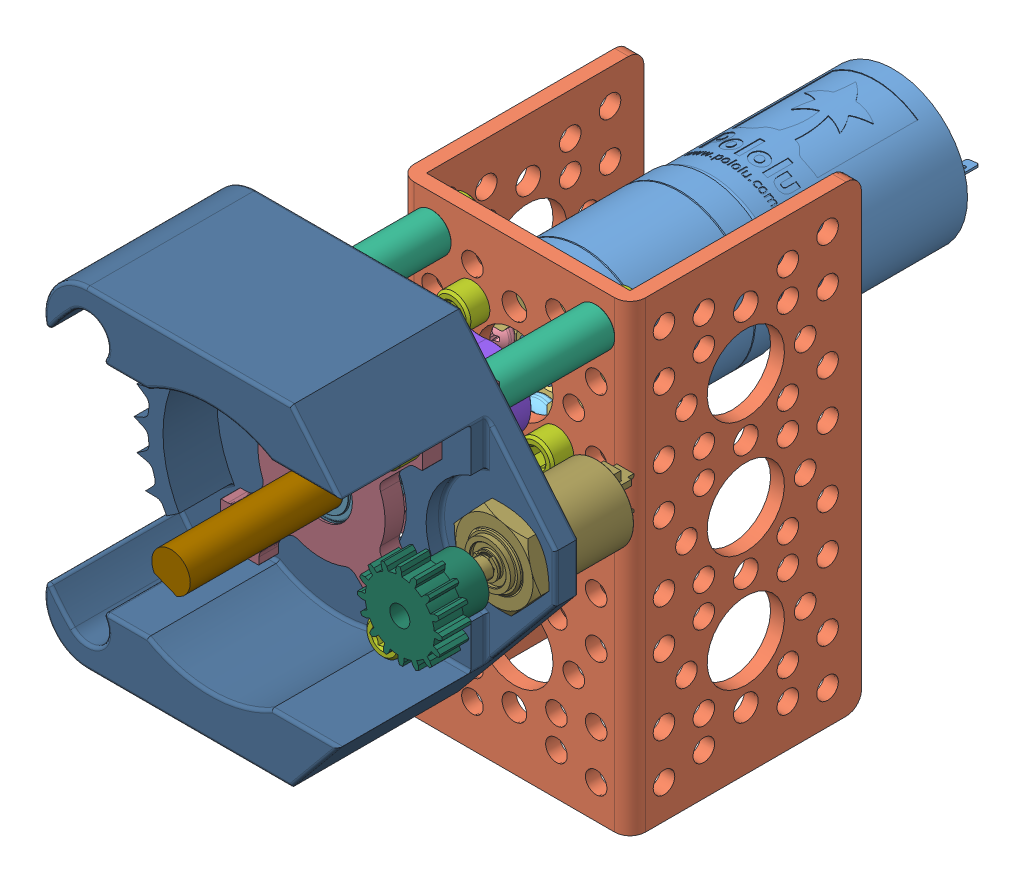
SolidWorks assembly Corner Steering Assembly, configuration Clockwise. Lengths in mm.
Overall size (61.41 84.4 123.14).
39 component instances, 15 part files, 66 mates.
Components (placement in the parent):
- 25mm Motor-1: 25mm Motor [Default] at (-12.6524 50.0026 57.4227) size (25 25 72.5)
- 3 Aluminum Channel-1: 3 Aluminum Channel [Default] at (-0.8274 -7.1474 82.4017) x (1 0 0) z (0 1 0) size (38.1 38.1 76.2)
- Motor mount f-1: Motor mount f [Default] at (-52.2349 29.3985 53.5592) x (-1 0 0) z (0 1 0) size (25.4 7.22 25.4)
  - 555104-1: 555104 [Default] at (-70.4575 22.2385 20.6041) size (25.4 4.54 25.4)
  - 555104 screw (M2.6)_92005A056-1: 555104 screw (M2.6)_92005A056 [Default] at (-77.9575 19.5085 20.6041) x (1 0 0) z (0 1 0) size (5 5 6.06)
  - 555104 screw (M2.6)_92005A056-2: 555104 screw (M2.6)_92005A056 [Default] at (-62.9575 19.5085 20.6041) x (1 0 0) z (0 1 0) size (5 5 6.06)
  - 555104 screw (M3)_92005A112-1: 555104 screw (M3)_92005A112 [Default] at (-70.4575 19.5085 12.1041) x (1 0 0) z (0 1 0) size (6 6 6.48)
  - 555104 screw (M3)_92005A112-2: 555104 screw (M3)_92005A112 [Default] at (-70.4575 19.5085 29.1041) x (1 0 0) z (0 1 0) size (6 6 6.48)
- 6_32 standoff-1: 6_32 standoff [Default] at (4.7522 63.473 82.4017) x (1 0 0) z (0 -1 0) size (6.34 19.26 6.34)
- 6_32 standoff-2: 6_32 standoff [Default] at (31.693 63.473 82.4017) x (1 0 0) z (0 -1 0) size (6.34 19.26 6.34)
- 6_32 standoff-3: 6_32 standoff [Default] at (31.693 36.5322 82.4017) x (1 0 0) z (0 -1 0) size (6.34 19.26 6.34)
- 6_32 standoff-4: 6_32 standoff [Default] at (4.7522 36.5322 82.4017) x (1 0 0) z (0 -1 0) size (6.34 19.26 6.34)
- 6-32_SHCS-1: 6-32_SHCS [6-32 SHCS X .250] at (31.693 63.473 86.4657) x (-0.923728 -0.383049 0) z (0 0 -1) size (5.74 5.74 9.86)
- 6-32_SHCS-2: 6-32_SHCS [6-32 SHCS X .250] at (4.7522 63.473 86.4657) x (-0.923728 -0.383049 0) z (0 0 -1) size (5.74 5.74 9.86)
- 6-32_SHCS-3: 6-32_SHCS [6-32 SHCS X .250] at (4.7522 36.5322 86.4657) x (-0.923728 -0.383049 0) z (0 0 -1) size (5.74 5.74 9.86)
- 6-32_SHCS-4: 6-32_SHCS [6-32 SHCS X .250] at (31.693 36.5322 86.4657) x (-0.923728 -0.383049 0) z (0 0 -1) size (5.74 5.74 9.86)
- 6-32_SHCS-5: 6-32_SHCS [6-32 SHCS X .250] at (11.3078 43.0878 76.0517) x (0.520489 -0.853869 0) z (0 0 1) size (5.74 5.74 9.86)
- 6-32_SHCS-6: 6-32_SHCS [6-32 SHCS X .250] at (25.1374 43.0878 76.0517) x (0.854812 0.518937 0) z (0 0 1) size (5.74 5.74 9.86)
- 6-32_SHCS-7: 6-32_SHCS [6-32 SHCS X .250] at (25.1374 56.9174 76.0517) size (5.74 5.74 9.86)
- 6-32_SHCS-8: 6-32_SHCS [6-32 SHCS X .250] at (11.3078 56.9174 76.0517) size (5.74 5.74 9.86)
- 4mm - 0.25in Clamping Shaft Coupler-1: 4mm - 0.25in Clamping Shaft Coupler [Default] at (18.2226 50.0026 93.5269) x (0.352101 0.935962 0) z (-0.935962 0.352101 0) size (12.7 15.24 16.29)
- .25 D Shaft-1: .25 D Shaft [Default] at (18.2226 50.0026 94.4873) x (-0.370952 -0.928652 0) z (-0.928652 0.370952 0) size (5.65 44.45 6.35)
- Encoder mount-1: Encoder mount [Default] at (18.2226 50.0026 110.9767) x (1 0 0) z (0 1 0) size (60.02 27.97 54.51)
- 6-32_L0_25 Spacer-1: 6-32_L0_25 Spacer [Default] at (4.7522 36.5322 104.6267) x (0 0 1) z (-0.967859 0.251494 0) size (6.35 6.35 6.35)
- 6-32_L0_25 Spacer-2: 6-32_L0_25 Spacer [Default] at (31.693 36.5322 104.6267) x (0 0 1) z (-0.631957 0.775004 0) size (6.35 6.35 6.35)
- 6-32_L0_25 Spacer-3: 6-32_L0_25 Spacer [Default] at (4.7522 63.473 104.6267) x (0 0 1) z (0 1 0) size (6.35 6.35 6.35)
- 6-32_L0_25 Spacer-4: 6-32_L0_25 Spacer [Default] at (31.693 63.473 104.6267) x (0 0 1) z (0 1 0) size (6.35 6.35 6.35)
- Absolute Encoder-1: Absolute Encoder [BEARING VERSION] at (43.3686 50.0026 111.1545) x (0 0 1) z (0 -1 0) size (32.36 14.32 14.3)
- 0.25 Pillow Bearing Block-1: 0.25 Pillow Bearing Block [Default] at (-10.4858 48.289 82.9742) x (0 1 0) z (1 0 0) size (33.27 5.08 33.27)
  - 0.25 Beaing Block-1: 0.25 Beaing Block [Default] at (1.7135 18.4775 28.7084) size (33.27 5.08 33.27)
  - 0.25 Bearing-1: 0.25 Bearing [Default] at (1.7135 21.1636 28.7084) x (0.837169 0 0.546944) z (0.546944 0 -0.837169) size (12.7 4.76 12.7)
- 0.25 Pillow Bearing Block-2: 0.25 Pillow Bearing Block [Default] at (19.9362 78.711 132.6292) x (-1 0 0) z (0 -1 0) size (33.27 5.08 33.27)
  - 0.25 Beaing Block-1: 0.25 Beaing Block [Default] at (1.7135 18.4775 28.7084) size (33.27 5.08 33.27)
  - 0.25 Bearing-1: 0.25 Bearing [Default] at (1.7135 21.1636 28.7084) x (0.837169 0 0.546944) z (0.546944 0 -0.837169) size (12.7 4.76 12.7)
- 0.125in Bore 32 Pitch Shaft Mount Pinion Gear-1: 0.125in Bore 32 Pitch Shaft Mount Pinion Gear [Default] at (43.3686 50.0026 126.4072) x (-0.355189 -0.934794 0) z (0.934794 -0.355189 0) size (13.97 10.48 13.97)
- 6-32_SHCS-9: 6-32_SHCS [6-32 SHCS X .750] at (31.693 63.473 95.1017) size (5.74 5.74 22.56)
- 6-32_SHCS-10: 6-32_SHCS [6-32 SHCS X .750] at (4.7522 36.5322 95.1017) size (5.74 5.74 22.56)
- 6-32_SHCS-11: 6-32_SHCS [6-32 SHCS X .750] at (4.7522 63.473 95.1017) size (5.74 5.74 22.56)
- 6-32_SHCS-12: 6-32_SHCS [6-32 SHCS X .750] at (31.693 36.5322 95.1017) size (5.74 5.74 22.56)
Mates (geometry in assembly coordinates):
- Concentric1: concentric aligned: cylinder of 25mm Motor-1 through (18.2226 50.0026 50.7977) axis (0 0 1) radius 12.5; cylinder of 3 Aluminum Channel-1 through (18.2226 50.0026 82.4017) axis (0 0 1) radius 6.3627
- Concentric2: concentric aligned: cylinder of 3 Aluminum Channel-1 through (18.2226 50.0026 82.4017) axis (0 0 1) radius 6.3627; cylinder of Motor mount f-1/555104-1 through (18.2226 50.0026 77.0677) axis (0 0 1) radius 5
- Concentric6: concentric aligned: cylinder of 25mm Motor-1 through (18.2226 58.5026 72.9477) axis (0 0 1) radius 1.25; cylinder of Motor mount f-1/555104-1 through (18.2226 58.5026 80.1157) axis (0 0 1) radius 1.5
- Coincident2: coincident anti-aligned: plane of 25mm Motor-1 through (18.2226 50.0026 75.7977) normal (0 0 1); plane of Motor mount f-1/555104-1 through (18.2226 50.0026 75.7977) normal (0 0 -1)
- Concentric7: concentric aligned: cylinder of 3 Aluminum Channel-1 through (11.3078 56.9174 82.4017) axis (0 0 1) radius 1.778; cylinder of Motor mount f-1/555104-1 through (11.3078 56.9174 80.1157) axis (0 0 1) radius 1.3526
- Coincident4: coincident anti-aligned: plane of 3 Aluminum Channel-1 through (1.4586 69.0526 80.1157) normal (0 0 -1); plane of Motor mount f-1/555104-1 through (18.2226 50.0026 80.1157) normal (0 0 1)
- Concentric8: concentric anti-aligned: cylinder of 3 Aluminum Channel-1 through (4.7522 63.473 82.4017) axis (0 0 1) radius 1.778; cylinder of 6_32 standoff-1 through (4.7522 63.473 101.4517) axis (0 0 -1) radius 3.1712
- Concentric9: concentric aligned: cylinder of 3 Aluminum Channel-1 through (4.7522 63.473 82.4017) axis (0 0 1) radius 1.778; cylinder of 6-32_SHCS-2 through (4.7522 63.473 67.4157) axis (0 0 1) radius 2.8702
- Concentric10: concentric anti-aligned: cylinder of 3 Aluminum Channel-1 through (31.693 63.473 82.4017) axis (0 0 1) radius 1.778; cylinder of 6_32 standoff-2 through (31.693 63.473 101.4517) axis (0 0 -1) radius 3.1712
- Concentric11: concentric aligned: cylinder of 3 Aluminum Channel-1 through (31.693 63.473 82.4017) axis (0 0 1) radius 1.778; cylinder of 6-32_SHCS-1 through (31.693 63.473 67.4157) axis (0 0 1) radius 2.8702
- Concentric12: concentric anti-aligned: cylinder of 3 Aluminum Channel-1 through (31.693 36.5322 82.4017) axis (0 0 1) radius 1.778; cylinder of 6_32 standoff-3 through (31.693 36.5322 101.4517) axis (0 0 -1) radius 3.1712
- Concentric13: concentric aligned: cylinder of 3 Aluminum Channel-1 through (31.693 36.5322 82.4017) axis (0 0 1) radius 1.778; cylinder of 6-32_SHCS-4 through (31.693 36.5322 67.4157) axis (0 0 1) radius 2.8702
- Concentric14: concentric anti-aligned: cylinder of 3 Aluminum Channel-1 through (4.7522 36.5322 82.4017) axis (0 0 1) radius 1.778; cylinder of 6_32 standoff-4 through (4.7522 36.5322 101.4517) axis (0 0 -1) radius 3.1712
- Concentric15: concentric aligned: cylinder of 3 Aluminum Channel-1 through (4.7522 36.5322 82.4017) axis (0 0 1) radius 1.778; cylinder of 6-32_SHCS-3 through (4.7522 36.5322 67.4157) axis (0 0 1) radius 2.8702
- Concentric16: concentric anti-aligned: cylinder of 3 Aluminum Channel-1 through (25.1374 56.9174 82.4017) axis (0 0 1) radius 1.778; cylinder of 6-32_SHCS-7 through (25.1374 56.9174 95.1017) axis (0 0 -1) radius 2.8702
- Concentric17: concentric anti-aligned: cylinder of 3 Aluminum Channel-1 through (25.1374 43.0878 82.4017) axis (0 0 1) radius 1.778; cylinder of 6-32_SHCS-6 through (25.1374 43.0878 95.1017) axis (0 0 -1) radius 2.8702
- Concentric18: concentric anti-aligned: cylinder of 3 Aluminum Channel-1 through (11.3078 43.0878 82.4017) axis (0 0 1) radius 1.778; cylinder of 6-32_SHCS-5 through (11.3078 43.0878 95.1017) axis (0 0 -1) radius 2.8702
- Concentric19: concentric anti-aligned: cylinder of 3 Aluminum Channel-1 through (11.3078 56.9174 82.4017) axis (0 0 1) radius 1.778; cylinder of 6-32_SHCS-8 through (11.3078 56.9174 95.1017) axis (0 0 -1) radius 2.8702
- Coincident5: coincident anti-aligned: plane of 3 Aluminum Channel-1 through (37.2726 69.0526 82.4017) normal (0 0 1); plane of 6-32_SHCS-8 through (11.3078 56.9174 82.4017) normal (0 0 -1)
- Coincident6: coincident anti-aligned: plane of 3 Aluminum Channel-1 through (37.2726 69.0526 82.4017) normal (0 0 1); plane of 6-32_SHCS-7 through (25.1374 56.9174 82.4017) normal (0 0 -1)
- Coincident7: coincident anti-aligned: plane of 3 Aluminum Channel-1 through (37.2726 69.0526 82.4017) normal (0 0 1); plane of 6-32_SHCS-6 through (25.1374 43.0878 82.4017) normal (0 0 -1)
- Coincident8: coincident anti-aligned: plane of 3 Aluminum Channel-1 through (37.2726 69.0526 82.4017) normal (0 0 1); plane of 6-32_SHCS-5 through (11.3078 43.0878 82.4017) normal (0 0 -1)
- Coincident9: coincident anti-aligned: plane of 3 Aluminum Channel-1 through (37.2726 69.0526 82.4017) normal (0 0 1); plane of 6_32 standoff-1 through (4.7522 63.473 82.4017) normal (0 0 -1)
- Coincident10: coincident anti-aligned: plane of 3 Aluminum Channel-1 through (37.2726 69.0526 82.4017) normal (0 0 1); plane of 6_32 standoff-2 through (31.693 63.473 82.4017) normal (0 0 -1)
- Coincident11: coincident anti-aligned: plane of 3 Aluminum Channel-1 through (37.2726 69.0526 82.4017) normal (0 0 1); plane of 6_32 standoff-3 through (31.693 36.5322 82.4017) normal (0 0 -1)
- Coincident12: coincident anti-aligned: plane of 3 Aluminum Channel-1 through (37.2726 69.0526 82.4017) normal (0 0 1); plane of 6_32 standoff-4 through (4.7522 36.5322 82.4017) normal (0 0 -1)
- Coincident13: coincident anti-aligned: plane of 3 Aluminum Channel-1 through (1.4586 69.0526 80.1157) normal (0 0 -1); plane of 6-32_SHCS-2 through (4.7522 63.473 80.1157) normal (0 0 1)
- Coincident14: coincident anti-aligned: plane of 3 Aluminum Channel-1 through (1.4586 69.0526 80.1157) normal (0 0 -1); plane of 6-32_SHCS-1 through (31.693 63.473 80.1157) normal (0 0 1)
- Coincident15: coincident anti-aligned: plane of 3 Aluminum Channel-1 through (1.4586 69.0526 80.1157) normal (0 0 -1); plane of 6-32_SHCS-4 through (31.693 36.5322 80.1157) normal (0 0 1)
- Coincident16: coincident anti-aligned: plane of 3 Aluminum Channel-1 through (1.4586 69.0526 80.1157) normal (0 0 -1); plane of 6-32_SHCS-3 through (4.7522 36.5322 80.1157) normal (0 0 1)
- Concentric20: concentric anti-aligned: cylinder of .25 D Shaft-1 through (18.2226 50.0026 157.9873) axis (0 0 -1) radius 3.175; cylinder of 4mm - 0.25in Clamping Shaft Coupler-1 through (18.2226 50.0026 93.5269) axis (0 0 1) radius 3.175
- Concentric21: concentric anti-aligned: cylinder of .25 D Shaft-1 through (18.2226 50.0026 157.9873) axis (0 0 -1) radius 3.175; cylinder of 25mm Motor-1 through (18.2226 50.0026 75.7977) axis (0 0 1) radius 2
- Coincident17: coincident anti-aligned: plane of 6-32_SHCS-7 through (25.1374 56.9174 85.9069) normal (0 0 1); plane of 4mm - 0.25in Clamping Shaft Coupler-1 through (18.2226 50.0026 85.9069) normal (0 0 -1)
- Concentric22: concentric anti-aligned: cylinder of Encoder mount-1 through (4.7522 36.5322 104.6267) axis (0 0 1) radius 3.2258; cylinder of 6-32_L0_25 Spacer-1 through (4.7522 36.5322 110.9767) axis (0 0 -1) radius 3.175
- Concentric23: concentric anti-aligned: cylinder of Encoder mount-1 through (31.693 36.5322 104.6267) axis (0 0 1) radius 3.2258; cylinder of 6-32_L0_25 Spacer-2 through (31.693 36.5322 110.9767) axis (0 0 -1) radius 3.175
- Concentric24: concentric anti-aligned: cylinder of Encoder mount-1 through (4.7522 63.473 104.6267) axis (0 0 1) radius 3.2258; cylinder of 6-32_L0_25 Spacer-3 through (4.7522 63.473 110.9767) axis (0 0 -1) radius 3.175
- Concentric25: concentric anti-aligned: cylinder of Encoder mount-1 through (31.693 63.473 104.6267) axis (0 0 1) radius 3.2258; cylinder of 6-32_L0_25 Spacer-4 through (31.693 63.473 110.9767) axis (0 0 -1) radius 3.175
- Concentric26: concentric aligned: cylinder of 4mm - 0.25in Clamping Shaft Coupler-1 through (18.2226 50.0026 85.9069) axis (0 0 1) radius 6.35; cylinder of Encoder mount-1 through (18.2226 50.0026 104.6267) axis (0 0 1) radius 10.795
- Coincident19: coincident aligned: plane of Encoder mount-1 through (18.2226 50.0026 110.9767) normal (0 0 1); plane of 6-32_L0_25 Spacer-3 through (4.7522 63.473 110.9767) normal (0 0 1)
- Coincident20: coincident aligned: plane of Encoder mount-1 through (18.2226 50.0026 110.9767) normal (0 0 1); plane of 6-32_L0_25 Spacer-1 through (4.7522 36.5322 110.9767) normal (0 0 1)
- Coincident21: coincident aligned: plane of Encoder mount-1 through (18.2226 50.0026 110.9767) normal (0 0 1); plane of 6-32_L0_25 Spacer-2 through (31.693 36.5322 110.9767) normal (0 0 1)
- Coincident22: coincident aligned: plane of Encoder mount-1 through (18.2226 50.0026 110.9767) normal (0 0 1); plane of 6-32_L0_25 Spacer-4 through (31.693 63.473 110.9767) normal (0 0 1)
- Parallel1: parallel aligned: plane of 3 Aluminum Channel-1 through (-0.8274 69.0526 82.4017) normal (0 1 0); plane of Encoder mount-1 through (18.2226 77.2567 104.6267) normal (0 1 0)
- Concentric27: concentric aligned: cylinder of Encoder mount-1 through (43.3686 50.0026 104.6267) axis (0 0 1) radius 5.08; cylinder of Absolute Encoder-1 through (43.3686 50.0026 111.1545) axis (0 0 1) radius 6.096
- Coincident24: coincident anti-aligned: plane of Encoder mount-1 through (18.2226 50.0026 104.6267) normal (0 0 -1); plane of Absolute Encoder-1 through (38.949 50.0026 104.6267) normal (0 0 1)
- Parallel2: parallel aligned: plane of 3 Aluminum Channel-1 through (37.2726 69.0526 44.3017) normal (1 0 0); plane of Absolute Encoder-1 through (45.9975 52.8626 94.3419) normal (1 0 0)
- Parallel3: parallel aligned: plane of 3 Aluminum Channel-1 through (-0.8274 69.0526 82.4017) normal (0 1 0); plane of Encoder mount-1
- Concentric28: concentric anti-aligned: cylinder of 0.25 Pillow Bearing Block-2/0.25 Bearing-1 through (18.2226 50.0026 113.8469) axis (0 0 -1) radius 3.175; cylinder of 0.25 Pillow Bearing Block-1/0.25 Bearing-1 through (18.2226 50.0026 101.7565) axis (0 0 1) radius 3.175
- Concentric29: concentric aligned: cylinder of 0.25 Pillow Bearing Block-2/0.25 Bearing-1 through (18.2226 50.0026 113.8469) axis (0 0 -1) radius 3.175; cylinder of .25 D Shaft-1 through (18.2226 50.0026 157.9873) axis (0 0 -1) radius 3.175
- Coincident30: coincident anti-aligned: plane of 6-32_L0_25 Spacer-4 through (31.693 63.473 110.9767) normal (0 0 1); plane of 0.25 Pillow Bearing Block-2/0.25 Beaing Block-1 through (18.2226 50.0026 110.9767) normal (0 0 -1)
- Concentric30: concentric aligned: cylinder of 0.25 Pillow Bearing Block-1/0.25 Beaing Block-1 through (31.693 36.5322 104.6267) axis (0 0 1) radius 1.778; cylinder of 6-32_L0_25 Spacer-2 through (31.693 36.5322 104.6267) axis (0 0 1) radius 1.651
- Concentric31: concentric anti-aligned: cylinder of 0.25 Pillow Bearing Block-1/0.25 Beaing Block-1 through (31.693 36.5322 104.6267) axis (0 0 1) radius 1.778; cylinder of 0.25 Pillow Bearing Block-2/0.25 Beaing Block-1 through (31.693 36.5322 110.9767) axis (0 0 -1) radius 1.778
- Coincident32: coincident anti-aligned: plane of 6-32_L0_25 Spacer-2 through (31.693 36.5322 104.6267) normal (0 0 -1); plane of 0.25 Pillow Bearing Block-1/0.25 Beaing Block-1 through (18.2226 50.0026 104.6267) normal (0 0 1)
- Coincident33: coincident anti-aligned: plane of 6_32 standoff-1 through (4.7522 63.473 101.4517) normal (0 0 1); plane of 0.25 Pillow Bearing Block-1/0.25 Beaing Block-1 through (18.2226 50.0026 101.4517) normal (0 0 -1)
- Coincident34: coincident aligned: plane of 4mm - 0.25in Clamping Shaft Coupler-1 through (23.1233 57.3597 94.4873) normal (0 0 -1); plane of .25 D Shaft-1 through (18.2226 50.0026 94.4873) normal (0 0 -1)
- Concentric32: concentric anti-aligned: cylinder of Absolute Encoder-1 through (43.3686 50.0026 121.9749) axis (0 0 -1) radius 1.5837; cylinder of 0.125in Bore 32 Pitch Shaft Mount Pinion Gear-1 through (43.3686 50.0026 115.9297) axis (0 0 1) radius 4.191
- Distance1: distance = 5.08 mm anti-aligned: plane of 0.125in Bore 32 Pitch Shaft Mount Pinion Gear-1 through (43.3686 50.0026 115.9297) normal (0 0 -1); plane of Absolute Encoder-1 through (46.1057 62.4041 110.8497) normal (0 0 1)
- Concentric33: concentric aligned: cylinder of 6_32 standoff-2 through (31.693 63.473 101.4517) axis (0 0 -1) radius 3.1712; cylinder of 6-32_SHCS-9 through (31.693 63.473 126.8517) axis (0 0 -1) radius 2.8702
- Concentric34: concentric aligned: cylinder of 6_32 standoff-1 through (4.7522 63.473 101.4517) axis (0 0 -1) radius 3.1712; cylinder of 6-32_SHCS-11 through (4.7522 63.473 126.8517) axis (0 0 -1) radius 2.8702
- Concentric35: concentric aligned: cylinder of 6_32 standoff-4 through (4.7522 36.5322 101.4517) axis (0 0 -1) radius 3.1712; cylinder of 6-32_SHCS-10 through (4.7522 36.5322 126.8517) axis (0 0 -1) radius 2.8702
- Concentric36: concentric aligned: cylinder of 6_32 standoff-3 through (31.693 36.5322 101.4517) axis (0 0 -1) radius 3.1712; cylinder of 6-32_SHCS-12 through (31.693 36.5322 126.8517) axis (0 0 -1) radius 2.8702
- Coincident36: coincident anti-aligned: plane of 0.25 Pillow Bearing Block-2/0.25 Beaing Block-1 through (18.2226 50.0026 114.1517) normal (0 0 1); plane of 6-32_SHCS-9 through (31.693 63.473 114.1517) normal (0 0 -1)
- Coincident37: coincident anti-aligned: plane of 0.25 Pillow Bearing Block-2/0.25 Beaing Block-1 through (18.2226 50.0026 114.1517) normal (0 0 1); plane of 6-32_SHCS-12 through (31.693 36.5322 114.1517) normal (0 0 -1)
- Coincident38: coincident anti-aligned: plane of 0.25 Pillow Bearing Block-2/0.25 Beaing Block-1 through (18.2226 50.0026 114.1517) normal (0 0 1); plane of 6-32_SHCS-11 through (4.7522 63.473 114.1517) normal (0 0 -1)
- Coincident39: coincident anti-aligned: plane of 0.25 Pillow Bearing Block-2/0.25 Beaing Block-1 through (18.2226 50.0026 114.1517) normal (0 0 1); plane of 6-32_SHCS-10 through (4.7522 36.5322 114.1517) normal (0 0 -1)
- Concentric37: concentric anti-aligned: cylinder of Absolute Encoder-1 through (-6.9234 50.0026 121.9749) axis (0 0 -1) radius 1.5837; cylinder of 0.125in Bore 32 Pitch Shaft Mount Pinion Gear-1 through (-6.9234 50.0026 115.9297) axis (0 0 1) radius 4.191
